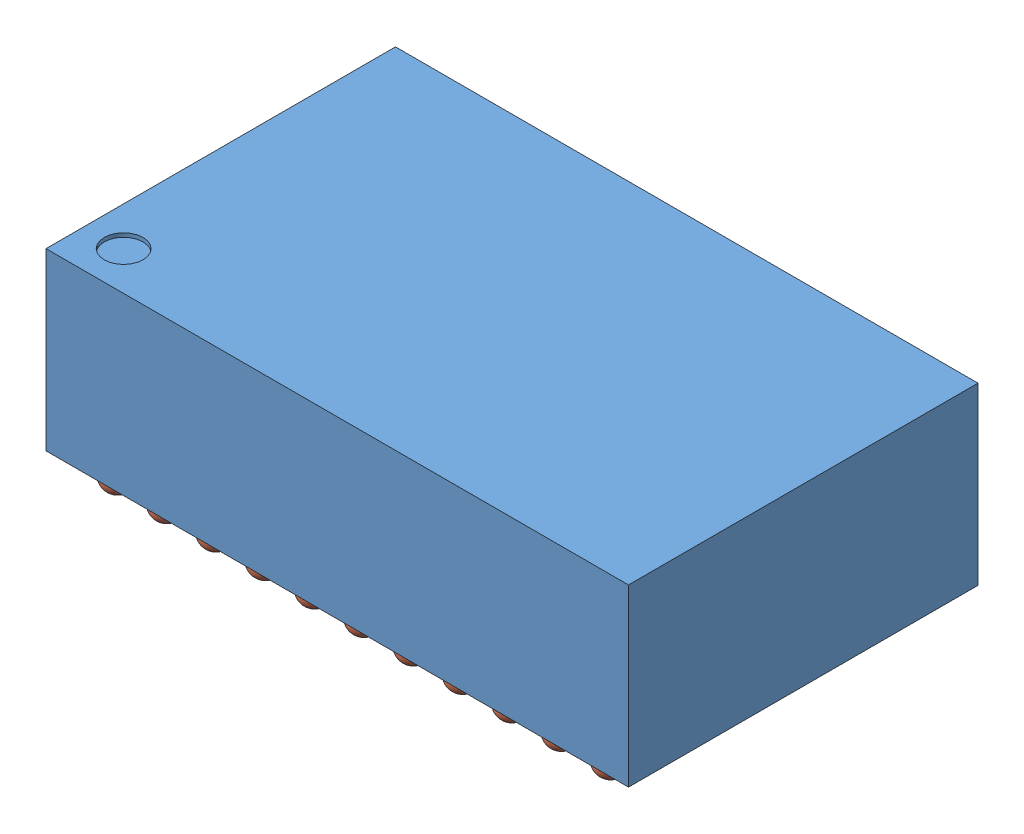
SolidWorks assembly Assem1, configuration Default. Lengths in mm.
Overall size (15 5.11 9).
97 component instances, 2 part files, 6 mates.
Components (placement in the parent):
- LTM4644-Body-1: LTM4644-Body [Default] at (0 0.6 0) size (15 4.51 9)
- LTM4644-Ball-1: LTM4644-Ball [Default] at (0 0.3 0) size (0.75 0.6 0.75)
- LTM4644-Ball-2: LTM4644-Ball [Default] at (-1.27 0.3 0) size (0.75 0.6 0.75)
- LTM4644-Ball-3: LTM4644-Ball [Default] at (-2.54 0.3 0) size (0.75 0.6 0.75)
- LTM4644-Ball-4: LTM4644-Ball [Default] at (-3.81 0.3 0) size (0.75 0.6 0.75)
- LTM4644-Ball-5: LTM4644-Ball [Default] at (-5.08 0.3 0) size (0.75 0.6 0.75)
- LTM4644-Ball-6: LTM4644-Ball [Default] at (-6.35 0.3 0) size (0.75 0.6 0.75)
- LTM4644-Ball-7: LTM4644-Ball [Default] at (0 0.3 0) x (-1 0 0) z (0 0 -1) size (0.75 0.6 0.75)
- LTM4644-Ball-8: LTM4644-Ball [Default] at (1.27 0.3 0) x (-1 0 0) z (0 0 -1) size (0.75 0.6 0.75)
- LTM4644-Ball-9: LTM4644-Ball [Default] at (2.54 0.3 0) x (-1 0 0) z (0 0 -1) size (0.75 0.6 0.75)
- LTM4644-Ball-10: LTM4644-Ball [Default] at (3.81 0.3 0) x (-1 0 0) z (0 0 -1) size (0.75 0.6 0.75)
- LTM4644-Ball-11: LTM4644-Ball [Default] at (5.08 0.3 0) x (-1 0 0) z (0 0 -1) size (0.75 0.6 0.75)
- LTM4644-Ball-12: LTM4644-Ball [Default] at (6.35 0.3 0) x (-1 0 0) z (0 0 -1) size (0.75 0.6 0.75)
- LTM4644-Ball-13: LTM4644-Ball [Default] at (0 0.3 1.27) size (0.75 0.6 0.75)
- LTM4644-Ball-14: LTM4644-Ball [Default] at (0 0.3 2.54) size (0.75 0.6 0.75)
- LTM4644-Ball-15: LTM4644-Ball [Default] at (0 0.3 3.81) size (0.75 0.6 0.75)
- LTM4644-Ball-16: LTM4644-Ball [Default] at (0 0.3 1.27) x (-1 0 0) z (0 0 -1) size (0.75 0.6 0.75)
- LTM4644-Ball-17: LTM4644-Ball [Default] at (0 0.3 2.54) x (-1 0 0) z (0 0 -1) size (0.75 0.6 0.75)
- LTM4644-Ball-18: LTM4644-Ball [Default] at (0 0.3 3.81) x (-1 0 0) z (0 0 -1) size (0.75 0.6 0.75)
- LTM4644-Ball-19: LTM4644-Ball [Default] at (1.27 0.3 1.27) x (-1 0 0) z (0 0 -1) size (0.75 0.6 0.75)
- LTM4644-Ball-20: LTM4644-Ball [Default] at (1.27 0.3 2.54) x (-1 0 0) z (0 0 -1) size (0.75 0.6 0.75)
- LTM4644-Ball-21: LTM4644-Ball [Default] at (1.27 0.3 3.81) x (-1 0 0) z (0 0 -1) size (0.75 0.6 0.75)
- LTM4644-Ball-22: LTM4644-Ball [Default] at (2.54 0.3 1.27) x (-1 0 0) z (0 0 -1) size (0.75 0.6 0.75)
- LTM4644-Ball-23: LTM4644-Ball [Default] at (2.54 0.3 2.54) x (-1 0 0) z (0 0 -1) size (0.75 0.6 0.75)
- LTM4644-Ball-24: LTM4644-Ball [Default] at (2.54 0.3 3.81) x (-1 0 0) z (0 0 -1) size (0.75 0.6 0.75)
- LTM4644-Ball-25: LTM4644-Ball [Default] at (3.81 0.3 1.27) x (-1 0 0) z (0 0 -1) size (0.75 0.6 0.75)
- LTM4644-Ball-26: LTM4644-Ball [Default] at (3.81 0.3 2.54) x (-1 0 0) z (0 0 -1) size (0.75 0.6 0.75)
- LTM4644-Ball-27: LTM4644-Ball [Default] at (3.81 0.3 3.81) x (-1 0 0) z (0 0 -1) size (0.75 0.6 0.75)
- LTM4644-Ball-28: LTM4644-Ball [Default] at (5.08 0.3 1.27) x (-1 0 0) z (0 0 -1) size (0.75 0.6 0.75)
- LTM4644-Ball-29: LTM4644-Ball [Default] at (5.08 0.3 2.54) x (-1 0 0) z (0 0 -1) size (0.75 0.6 0.75)
- LTM4644-Ball-30: LTM4644-Ball [Default] at (5.08 0.3 3.81) x (-1 0 0) z (0 0 -1) size (0.75 0.6 0.75)
- LTM4644-Ball-31: LTM4644-Ball [Default] at (6.35 0.3 1.27) x (-1 0 0) z (0 0 -1) size (0.75 0.6 0.75)
- LTM4644-Ball-32: LTM4644-Ball [Default] at (6.35 0.3 2.54) x (-1 0 0) z (0 0 -1) size (0.75 0.6 0.75)
- LTM4644-Ball-33: LTM4644-Ball [Default] at (6.35 0.3 3.81) x (-1 0 0) z (0 0 -1) size (0.75 0.6 0.75)
- LTM4644-Ball-34: LTM4644-Ball [Default] at (-1.27 0.3 1.27) size (0.75 0.6 0.75)
- LTM4644-Ball-35: LTM4644-Ball [Default] at (-1.27 0.3 2.54) size (0.75 0.6 0.75)
- LTM4644-Ball-36: LTM4644-Ball [Default] at (-1.27 0.3 3.81) size (0.75 0.6 0.75)
- LTM4644-Ball-37: LTM4644-Ball [Default] at (-2.54 0.3 1.27) size (0.75 0.6 0.75)
- LTM4644-Ball-38: LTM4644-Ball [Default] at (-2.54 0.3 2.54) size (0.75 0.6 0.75)
- LTM4644-Ball-39: LTM4644-Ball [Default] at (-2.54 0.3 3.81) size (0.75 0.6 0.75)
- LTM4644-Ball-40: LTM4644-Ball [Default] at (-3.81 0.3 1.27) size (0.75 0.6 0.75)
- LTM4644-Ball-41: LTM4644-Ball [Default] at (-3.81 0.3 2.54) size (0.75 0.6 0.75)
- LTM4644-Ball-42: LTM4644-Ball [Default] at (-3.81 0.3 3.81) size (0.75 0.6 0.75)
- LTM4644-Ball-43: LTM4644-Ball [Default] at (-5.08 0.3 1.27) size (0.75 0.6 0.75)
- LTM4644-Ball-44: LTM4644-Ball [Default] at (-5.08 0.3 2.54) size (0.75 0.6 0.75)
- LTM4644-Ball-45: LTM4644-Ball [Default] at (-5.08 0.3 3.81) size (0.75 0.6 0.75)
- LTM4644-Ball-46: LTM4644-Ball [Default] at (-6.35 0.3 1.27) size (0.75 0.6 0.75)
- LTM4644-Ball-47: LTM4644-Ball [Default] at (-6.35 0.3 2.54) size (0.75 0.6 0.75)
- LTM4644-Ball-48: LTM4644-Ball [Default] at (-6.35 0.3 3.81) size (0.75 0.6 0.75)
- LTM4644-Ball-49: LTM4644-Ball [Default] at (0 0.3 0) size (0.75 0.6 0.75)
- LTM4644-Ball-50: LTM4644-Ball [Default] at (0 0.3 0) x (-1 0 0) z (0 0 -1) size (0.75 0.6 0.75)
- LTM4644-Ball-51: LTM4644-Ball [Default] at (1.27 0.3 0) x (-1 0 0) z (0 0 -1) size (0.75 0.6 0.75)
- LTM4644-Ball-52: LTM4644-Ball [Default] at (2.54 0.3 0) x (-1 0 0) z (0 0 -1) size (0.75 0.6 0.75)
- LTM4644-Ball-53: LTM4644-Ball [Default] at (3.81 0.3 0) x (-1 0 0) z (0 0 -1) size (0.75 0.6 0.75)
- LTM4644-Ball-54: LTM4644-Ball [Default] at (5.08 0.3 0) x (-1 0 0) z (0 0 -1) size (0.75 0.6 0.75)
- LTM4644-Ball-55: LTM4644-Ball [Default] at (6.35 0.3 0) x (-1 0 0) z (0 0 -1) size (0.75 0.6 0.75)
- LTM4644-Ball-56: LTM4644-Ball [Default] at (-1.27 0.3 0) size (0.75 0.6 0.75)
- LTM4644-Ball-57: LTM4644-Ball [Default] at (-2.54 0.3 0) size (0.75 0.6 0.75)
- LTM4644-Ball-58: LTM4644-Ball [Default] at (-3.81 0.3 0) size (0.75 0.6 0.75)
- LTM4644-Ball-59: LTM4644-Ball [Default] at (-5.08 0.3 0) size (0.75 0.6 0.75)
- LTM4644-Ball-60: LTM4644-Ball [Default] at (-6.35 0.3 0) size (0.75 0.6 0.75)
- LTM4644-Ball-61: LTM4644-Ball [Default] at (0 0.3 -1.27) size (0.75 0.6 0.75)
- LTM4644-Ball-62: LTM4644-Ball [Default] at (0 0.3 -2.54) size (0.75 0.6 0.75)
- LTM4644-Ball-63: LTM4644-Ball [Default] at (0 0.3 -3.81) size (0.75 0.6 0.75)
- LTM4644-Ball-64: LTM4644-Ball [Default] at (0 0.3 -1.27) x (-1 0 0) z (0 0 -1) size (0.75 0.6 0.75)
- LTM4644-Ball-65: LTM4644-Ball [Default] at (0 0.3 -2.54) x (-1 0 0) z (0 0 -1) size (0.75 0.6 0.75)
- LTM4644-Ball-66: LTM4644-Ball [Default] at (0 0.3 -3.81) x (-1 0 0) z (0 0 -1) size (0.75 0.6 0.75)
- LTM4644-Ball-67: LTM4644-Ball [Default] at (1.27 0.3 -1.27) x (-1 0 0) z (0 0 -1) size (0.75 0.6 0.75)
- LTM4644-Ball-68: LTM4644-Ball [Default] at (1.27 0.3 -2.54) x (-1 0 0) z (0 0 -1) size (0.75 0.6 0.75)
- LTM4644-Ball-69: LTM4644-Ball [Default] at (1.27 0.3 -3.81) x (-1 0 0) z (0 0 -1) size (0.75 0.6 0.75)
- LTM4644-Ball-70: LTM4644-Ball [Default] at (2.54 0.3 -1.27) x (-1 0 0) z (0 0 -1) size (0.75 0.6 0.75)
- LTM4644-Ball-71: LTM4644-Ball [Default] at (2.54 0.3 -2.54) x (-1 0 0) z (0 0 -1) size (0.75 0.6 0.75)
- LTM4644-Ball-72: LTM4644-Ball [Default] at (2.54 0.3 -3.81) x (-1 0 0) z (0 0 -1) size (0.75 0.6 0.75)
- LTM4644-Ball-73: LTM4644-Ball [Default] at (3.81 0.3 -1.27) x (-1 0 0) z (0 0 -1) size (0.75 0.6 0.75)
- LTM4644-Ball-74: LTM4644-Ball [Default] at (3.81 0.3 -2.54) x (-1 0 0) z (0 0 -1) size (0.75 0.6 0.75)
- LTM4644-Ball-75: LTM4644-Ball [Default] at (3.81 0.3 -3.81) x (-1 0 0) z (0 0 -1) size (0.75 0.6 0.75)
- LTM4644-Ball-76: LTM4644-Ball [Default] at (5.08 0.3 -1.27) x (-1 0 0) z (0 0 -1) size (0.75 0.6 0.75)
- LTM4644-Ball-77: LTM4644-Ball [Default] at (5.08 0.3 -2.54) x (-1 0 0) z (0 0 -1) size (0.75 0.6 0.75)
- LTM4644-Ball-78: LTM4644-Ball [Default] at (5.08 0.3 -3.81) x (-1 0 0) z (0 0 -1) size (0.75 0.6 0.75)
- LTM4644-Ball-79: LTM4644-Ball [Default] at (6.35 0.3 -1.27) x (-1 0 0) z (0 0 -1) size (0.75 0.6 0.75)
- LTM4644-Ball-80: LTM4644-Ball [Default] at (6.35 0.3 -2.54) x (-1 0 0) z (0 0 -1) size (0.75 0.6 0.75)
- LTM4644-Ball-81: LTM4644-Ball [Default] at (6.35 0.3 -3.81) x (-1 0 0) z (0 0 -1) size (0.75 0.6 0.75)
- LTM4644-Ball-82: LTM4644-Ball [Default] at (-1.27 0.3 -1.27) size (0.75 0.6 0.75)
- LTM4644-Ball-83: LTM4644-Ball [Default] at (-1.27 0.3 -2.54) size (0.75 0.6 0.75)
- LTM4644-Ball-84: LTM4644-Ball [Default] at (-1.27 0.3 -3.81) size (0.75 0.6 0.75)
- LTM4644-Ball-85: LTM4644-Ball [Default] at (-2.54 0.3 -1.27) size (0.75 0.6 0.75)
- LTM4644-Ball-86: LTM4644-Ball [Default] at (-2.54 0.3 -2.54) size (0.75 0.6 0.75)
- LTM4644-Ball-87: LTM4644-Ball [Default] at (-2.54 0.3 -3.81) size (0.75 0.6 0.75)
- LTM4644-Ball-88: LTM4644-Ball [Default] at (-3.81 0.3 -1.27) size (0.75 0.6 0.75)
- LTM4644-Ball-89: LTM4644-Ball [Default] at (-3.81 0.3 -2.54) size (0.75 0.6 0.75)
- LTM4644-Ball-90: LTM4644-Ball [Default] at (-3.81 0.3 -3.81) size (0.75 0.6 0.75)
- LTM4644-Ball-91: LTM4644-Ball [Default] at (-5.08 0.3 -1.27) size (0.75 0.6 0.75)
- LTM4644-Ball-92: LTM4644-Ball [Default] at (-5.08 0.3 -2.54) size (0.75 0.6 0.75)
- LTM4644-Ball-93: LTM4644-Ball [Default] at (-5.08 0.3 -3.81) size (0.75 0.6 0.75)
- LTM4644-Ball-94: LTM4644-Ball [Default] at (-6.35 0.3 -1.27) size (0.75 0.6 0.75)
- LTM4644-Ball-95: LTM4644-Ball [Default] at (-6.35 0.3 -2.54) size (0.75 0.6 0.75)
- LTM4644-Ball-96: LTM4644-Ball [Default] at (-6.35 0.3 -3.81) size (0.75 0.6 0.75)
Mates (geometry in assembly coordinates):
- Coincident1: coincident aligned: plane of LTM4644-Body-1 through (0 0.6 0) normal (1 0 0)
- Coincident2: coincident aligned: plane of LTM4644-Body-1 through (0 0.6 0) normal (0 0 1)
- Distance1: distance = 0.6 mm aligned: plane of LTM4644-Body-1 through (0 0.6 0) normal (0 1 0)
- Coincident4: coincident aligned: plane of LTM4644-Body-1 through (0 0.6 0) normal (1 0 0); plane of LTM4644-Ball-1 through (0 0.3 0) normal (1 0 0)
- Coincident5: coincident aligned: plane of LTM4644-Ball-1 through (0 0.3 0) normal (0 0 1)
- Coincident6: coincident anti-aligned: plane of LTM4644-Body-1 through (0 0.6 0) normal (0 -1 0); plane of LTM4644-Ball-1 through (0 0.6 0) normal (0 1 0)
